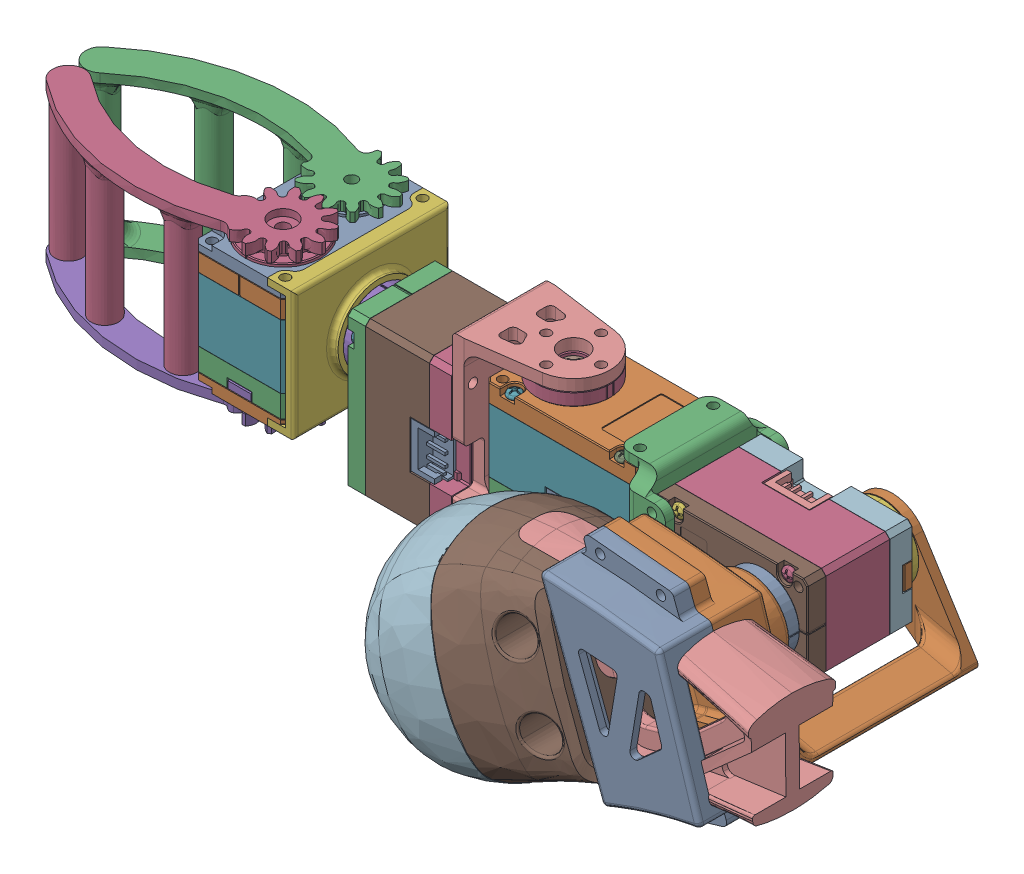
SolidWorks assembly loco-manipulator_right_urdf, configuration Default. Lengths in mm.
Overall size (198.32 72.36 70.45).
5 component instances, 5 part files, 13 mates.
Components (placement in the parent):
- link_1_right-1: link_1_right [Default] at origin size (36.26 44.35 61)
- link_2_right-1: link_2_right [Default] at (-272.1387 -81.5409 -106.5) x (0 -1 0) z (0 0 1) size (29.02 72.1 29.02)
- link_3-1: link_3 [Default] at (-339.2387 -81.5409 -114.5) x (0 0 -1) z (1 0 0) size (20 41.5 50.52)
- gripper-1: gripper [Default] at (-381.2387 -73.5409 -107) x (-1 0 0) z (0 1 0) size (67.06 34.46 34.6)
- calf_right-1: calf_right [Default] at (-163.1832 -115.6303 121.5) x (-0.324223 0.945981 0) z (0.945981 0.324223 0) size (46.46 40.9 87.61)
Mates (geometry in assembly coordinates):
- Coincident1: coincident anti-aligned: plane of link_1_right-1 through (-272.1387 -81.5409 -100) normal (0 0 -1); plane of link_2_right-1 through (-272.1387 -81.5409 -100) normal (0 0 1)
- Concentric1: concentric anti-aligned: cylinder of link_1_right-1 through (-272.1387 -81.5409 -70) axis (0 0 -1) radius 3.25; cylinder of link_2_right-1 through (-272.1387 -81.5409 -102.9) axis (0 0 1) radius 8
- Coincident2: coincident anti-aligned: plane of link_2_right-1 through (-325.2387 -67.0409 -114.5) normal (0 1 0); plane of link_3-1 through (-325.2387 -67.0409 -114.5) normal (0 -1 0)
- Concentric2: concentric aligned: cylinder of link_2_right-1 through (-325.2387 -69.9409 -114.5) axis (0 1 0) radius 8; cylinder of link_3-1 through (-325.2387 -67.0409 -114.5) axis (0 1 0) radius 3
- Coincident3: coincident anti-aligned: plane of link_3-1 through (-367.7387 -81.5409 -114.5) normal (-1 0 0); plane of gripper-1 through (-367.7387 -81.5409 -114.5) normal (1 0 0)
- Concentric3: concentric aligned: cylinder of link_3-1 through (-364.8387 -81.5409 -114.5) axis (-1 0 0) radius 8; cylinder of gripper-1 through (-361.2387 -81.5409 -114.5) axis (-1 0 0) radius 3.5
- Parallel1: parallel aligned: plane of link_2_right-1 through (-300.7387 -73.5409 -124.5) normal (0 0 -1); plane of link_3-1 through (-361.2387 -72.0409 -124.5) normal (0 0 -1)
- Parallel2: parallel aligned: plane of link_3-1 through (-361.2387 -72.0409 -104.5) normal (0 1 0); plane of gripper-1 through (-381.2387 -67.5409 -114.5) normal (0 1 0)
- Parallel3: parallel aligned: plane of link_2_right-1 through (-262.6387 -71.5409 -106.5) normal (0 1 0)
- Width1: width: plane of calf_right-1 through (-237.3808 -87.6033 -83) normal (0 0 -1); plane of link_1_right-1 through (-237.3799 -87.6079 -80) normal (0 0 1); plane of calf_right-1 through (0 0 -85) normal (0 0 -1); plane of link_1_right-1 through (0 0 -78) normal (0 0 1)
- Angle1: planar angle = 0.29147 rad: plane of calf_right-1 through (-243.6499 -161.1426 -63) normal (0.999949 0.010147 0); plane of link_1_right-1 through (-258.4049 -80.3922 -51.5) normal (0.954857 0.297065 0)
- Distance1: distance = 15.47 mm: point of calf_right-1; plane of link_1_right-1 through (-258.4049 -80.3922 -51.5) normal (0.954857 0.297065 0)
- Distance2: distance = 24.83 mm: point of calf_right-1; plane of link_1_right-1 through (7.2264 -24.5054 -78) normal (0.282848 -0.959165 0)
